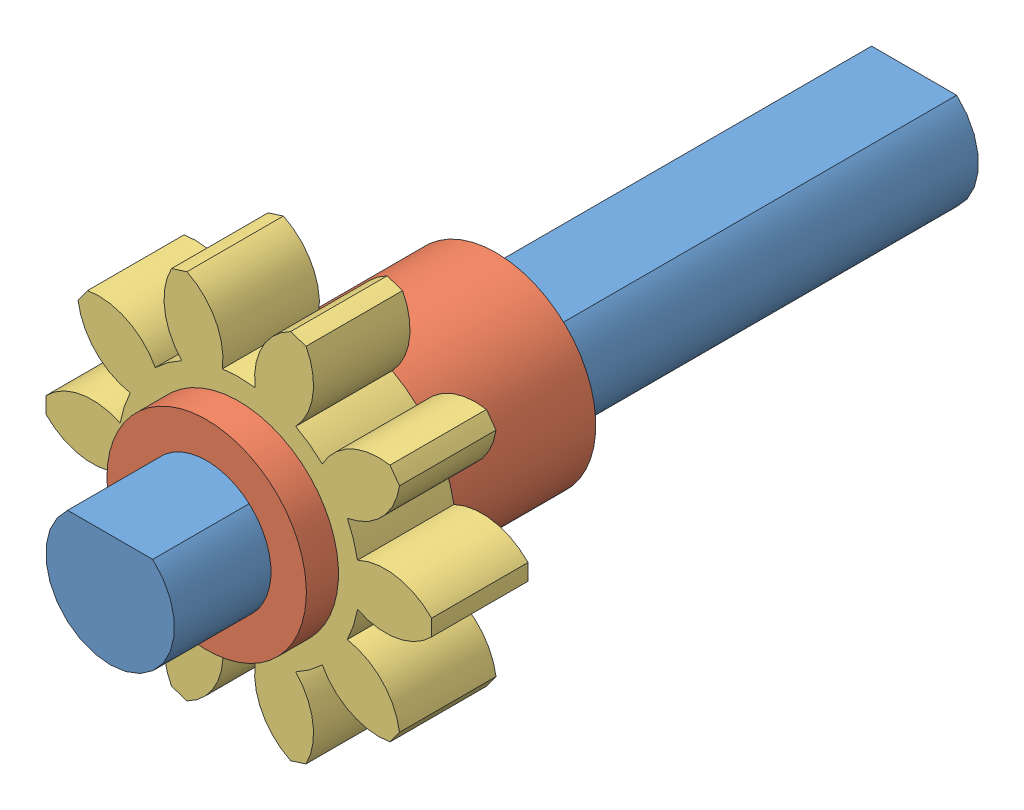
SolidWorks assembly inputShaft, configuration Default. Lengths in mm.
Overall size (12 11.56 25).
4 component instances, 3 part files, 7 mates.
Components (placement in the parent):
- axle-1: axle [25mm tall] at (6.1264 7.6622 19.0178) size (4 3.5 25)
- spacer-1: spacer [1mm tall] at (6.1264 7.6622 15.0178) size (6.2 6.2 1)
- root_gear-1: root_gear [10T 1.0Mod] at (6.1264 7.6622 12.0178) size (12 11.56 3)
- spacer-2: spacer [5mm tall] at (6.1264 7.6622 12.0178) x (-0.850804 -0.525483 0) z (0 0 -1) size (6.2 6.2 5)
Mates (geometry in assembly coordinates):
- Concentric1: concentric anti-aligned: cylinder of axle-1 through (6.1264 7.6622 -5.9822) axis (0 0 1) radius 2; cylinder of spacer-1 through (6.1264 7.6622 16.0178) axis (0 0 -1) radius 2
- Distance1: distance = 3 mm aligned: plane of spacer-1 through (6.1264 7.6622 16.0178) normal (0 0 1); plane of axle-1 through (6.1264 7.6622 19.0178) normal (0 0 1)
- Coincident2: coincident anti-aligned: plane of axle-1 through (7.4493 9.1622 -5.9822) normal (0 1 0); plane of root_gear-1 through (4.8036 9.1622 12.0178) normal (0 -1 0)
- Coincident3: coincident anti-aligned: plane of spacer-1 through (6.1264 7.6622 15.0178) normal (0 0 -1); plane of root_gear-1 through (6.1264 7.6622 15.0178) normal (0 0 1)
- Concentric3: concentric aligned: cylinder of axle-1 through (6.1264 7.6622 -5.9822) axis (0 0 1) radius 2; cylinder of root_gear-1 through (6.1264 7.6622 12.0178) axis (0 0 1) radius 2
- Concentric41: concentric aligned: cylinder of axle-1 through (6.1264 7.6622 -5.9822) axis (0 0 1) radius 2; cylinder of spacer-2 through (6.1264 7.6622 7.0178) axis (0 0 1) radius 2
- Coincident4: coincident anti-aligned: plane of root_gear-1 through (6.1264 7.6622 12.0178) normal (0 0 -1); plane of spacer-2 through (6.1264 7.6622 12.0178) normal (0 0 1)
